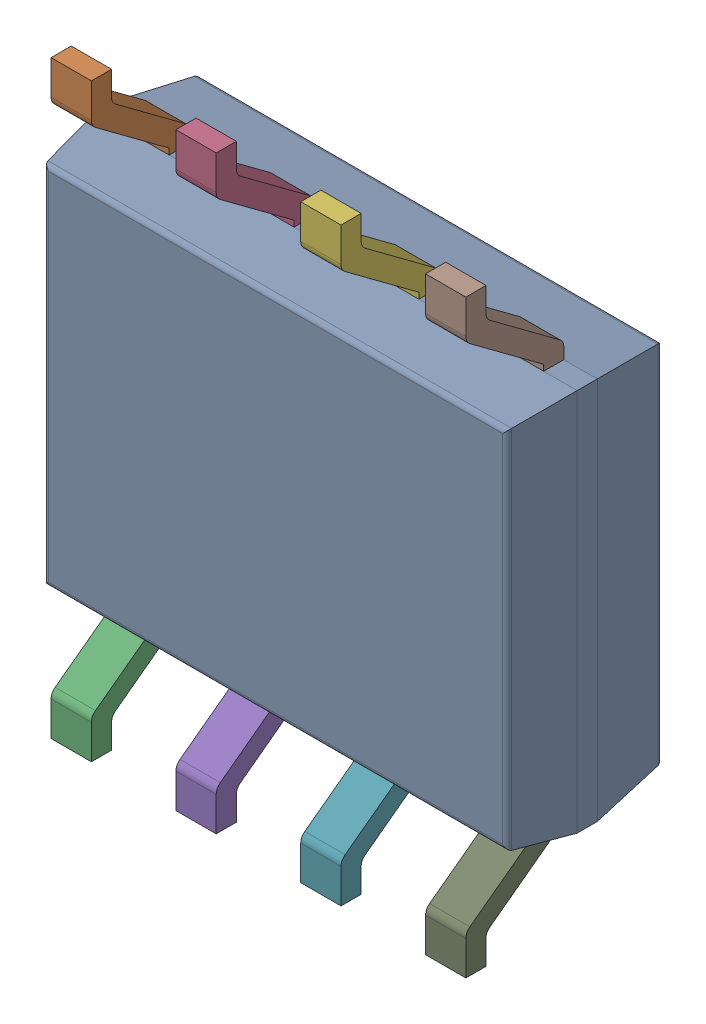
SolidWorks assembly IC1, configuration Default. Lengths in mm.
Overall size (4.9 6 1.75).
3 component instances, 2 part files, 0 mates.
Components (placement in the parent):
- 12042009920-1: 12042009920 [Default] at (124.46 94.742 -1.0914) x (0 -1 0) z (0 0 -1) size (6 4.9 1.75)
  - Body-1: Body [Default] at origin size (3.9 4.9 1.57)
  - PinsArrayLR-1: PinsArrayLR [Default] at origin size (6 4.22 1)
